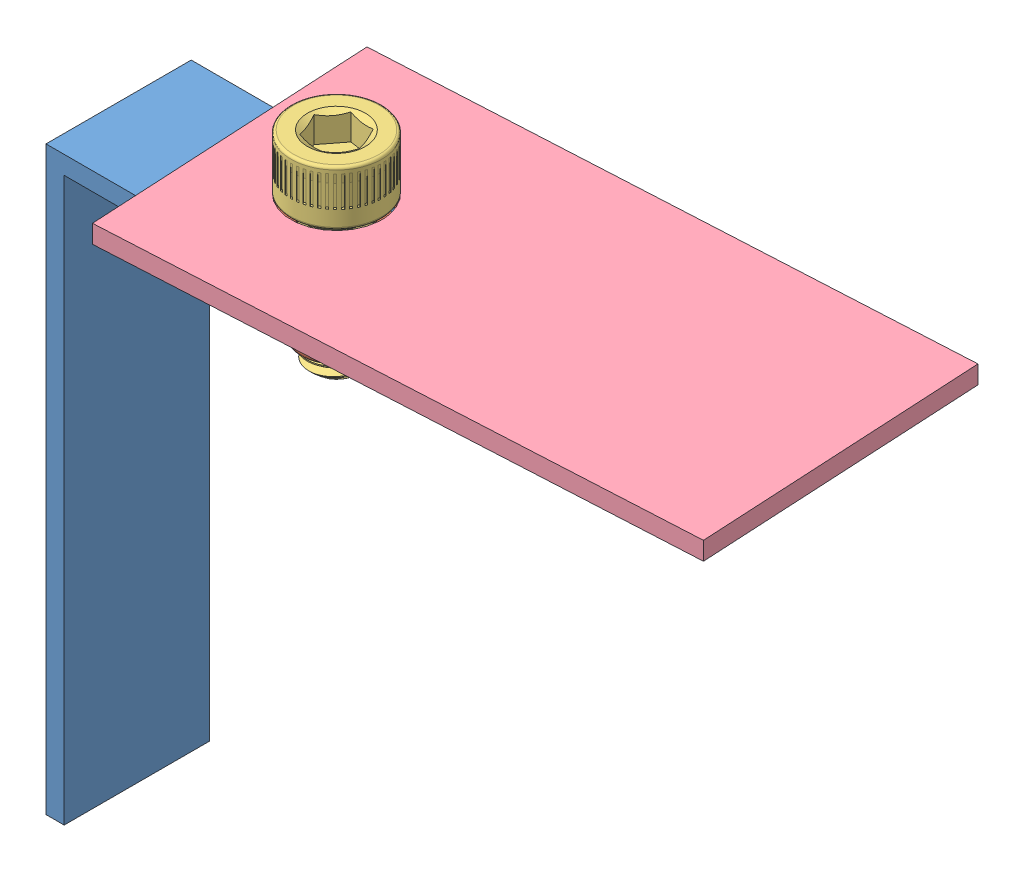
SolidWorks assembly clip nut example, configuration Default. Lengths in mm.
Overall size (61.36 58.28 28.07).
4 component instances, 4 part files, 6 mates.
Components (placement in the parent):
- tab boi-1: tab boi [Default] at origin size (25.4 50.8 12.7)
- 94850A120_No-Slip Clip-On Barrel Nut-1: 94850A120_No-Slip Clip-On Barrel Nut [94850A120] at (19.05 49.2125 6.35) x (0.999881 0 -0.015411) z (-0.015411 0 -0.999881) size (19.7 10.52 13.6)
- 91251A342_Black-Oxide Alloy Steel Socket Head Screw-1: 91251A342_Black-Oxide Alloy Steel Socket Head Screw [91251A342] at (19.05 49.4505 6.35) x (0.925646 0 -0.378391) z (0 1 0) size (7.94 7.94 17.97)
- thing-1: thing [Default] at (61.3599 51.8 16.5627) x (-0.053322 0 -0.998577) z (0.998577 0 -0.053322) size (25.4 1.59 50.8)
Mates (geometry in assembly coordinates):
- Coincident1: coincident anti-aligned: plane of tab boi-1 through (0 49.2125 12.7) normal (0 -1 0); plane of 94850A120_No-Slip Clip-On Barrel Nut-1 through (12.7331 49.2125 0.4141) normal (0 1 0)
- Concentric1: concentric aligned: cylinder of tab boi-1 through (19.05 40.8 6.35) axis (0 1 0) radius 3.175; cylinder of 94850A120_No-Slip Clip-On Barrel Nut-1 through (19.05 48.8315 6.35) axis (0 1 0) radius 3.1369
- Concentric2: concentric anti-aligned: cylinder of 94850A120_No-Slip Clip-On Barrel Nut-1 through (19.05 48.8315 6.35) axis (0 1 0) radius 3.1369; cylinder of 91251A342_Black-Oxide Alloy Steel Socket Head Screw-1 through (19.05 40.6875 6.35) axis (0 -1 0) radius 3.9688
- Concentric3: concentric anti-aligned: cylinder of 94850A120_No-Slip Clip-On Barrel Nut-1 through (19.05 48.8315 6.35) axis (0 1 0) radius 3.1369; cylinder of thing-1 through (19.05 53.3875 6.35) axis (0 -1 0) radius 3.9688
- Distance1: distance = 1 mm anti-aligned: plane of tab boi-1 through (0 50.8 12.7) normal (0 1 0); plane of thing-1 through (61.3599 51.8 16.5627) normal (0 -1 0)
- Coincident3: coincident anti-aligned: plane of 91251A342_Black-Oxide Alloy Steel Socket Head Screw-1 through (15.5997 53.3875 7.7604) normal (0 -1 0); plane of thing-1 through (61.3599 53.3875 16.5627) normal (0 1 0)
